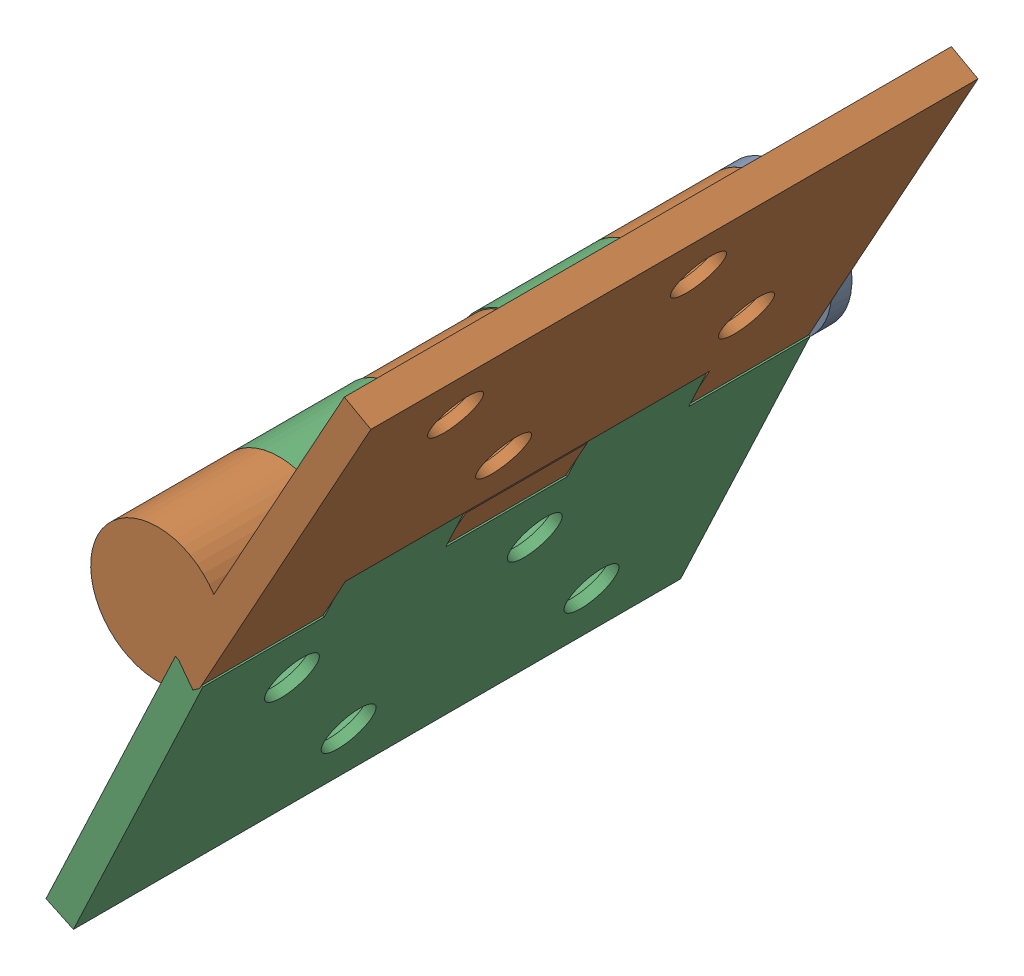
SolidWorks assembly Assem3, configuration Default. Lengths in mm.
Overall size (40.91 63.65 62).
3 component instances, 3 part files, 3 mates.
Components (placement in the parent):
- Part2-1: Part2 [Default] at (59.9801 23.1067 -2.2914) size (13.23 13.23 60)
- Plate 1-1: Plate 1 [Default] at (56.3025 41.5855 -2.2914) x (0.483628 0.875274 0) z (0 0 1) size (39.11 12.74 60)
- Plate 2-1: Plate 2 [Default] at (40.5577 10.7891 -2.2914) x (-0.426324 -0.90457 0) z (0 0 -1) size (39.11 12.74 60)
Mates (geometry in assembly coordinates):
- Hinge1: hinge aligned: cylinder of Plate 2-1 through (42.4801 29.2292 -8.2914) axis (0 0 -1) radius 6.6132; cylinder of Plate 1-1 through (42.4801 29.2292 3.7086) axis (0 0 -1) radius 6.5131; plane of Plate 1-1 through (60.9311 56.1655 27.7086) normal (0 0 1); plane of Plate 2-1 through (31.4491 -1.5005 27.7086) normal (0 0 1)
- Concentric1: concentric anti-aligned: cylinder of Part2-1 through (42.4801 29.2292 -43.6051) axis (0 0 1) radius 4; cylinder of Plate 1-1 through (42.4801 29.2292 -20.2914) axis (0 0 -1) radius 4
- Coincident3: coincident anti-aligned: plane of Part2-1 through (42.4801 29.2292 -32.2914) normal (0 0 1); plane of Plate 1-1 through (60.9311 56.1655 -32.2914) normal (0 0 -1)
